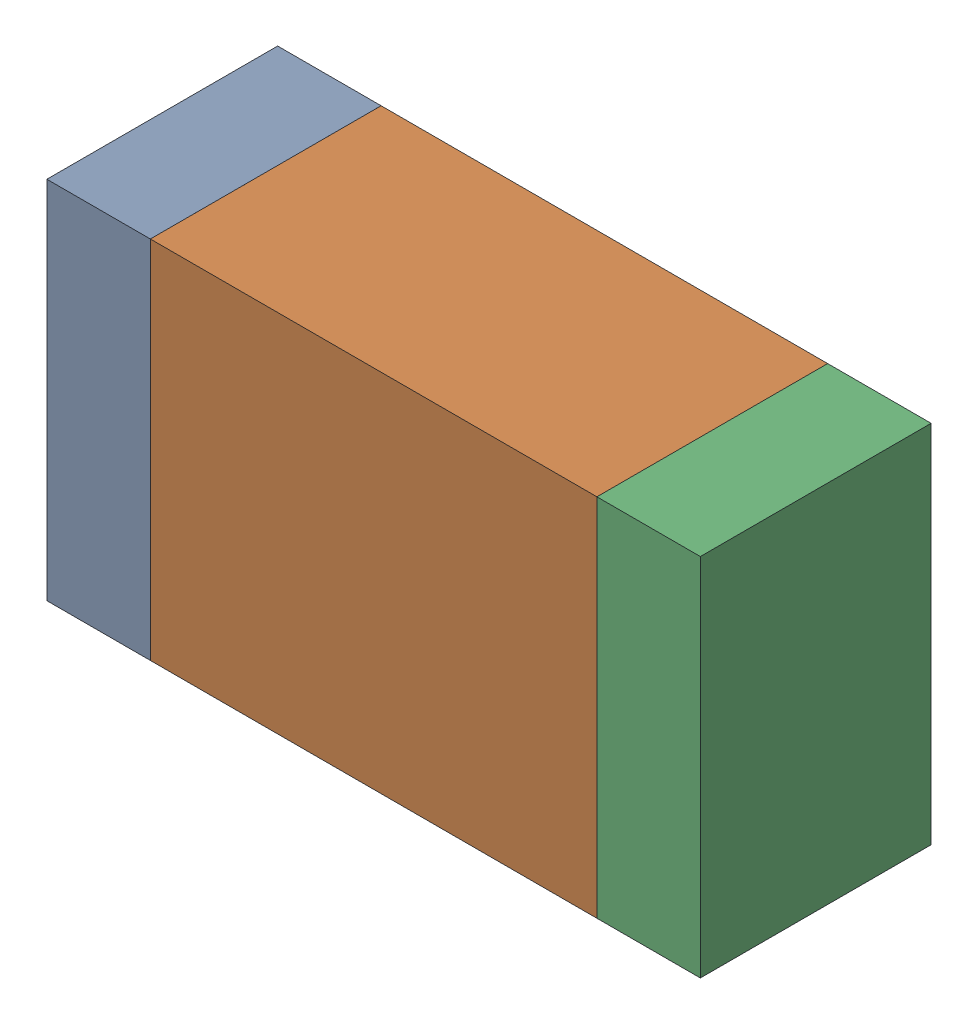
SolidWorks assembly F300_2PCB, configuration Default. Lengths in mm.
Overall size (1.7 0.95 0.6).
6 component instances, 2 part files, 0 mates.
Components (placement in the parent):
- 761615840-1: 761615840 [Default] at (159.7849 98.9999 0) size (0.27 0.95 0.6)
  - Extruded_37-1: Extruded_37 [Default] at origin size (0.27 0.95 0.6)
- 761615976-1: 761615976 [Default] at (160.4999 98.9999 0) size (1.16 0.95 0.6)
  - Extruded_38-1: Extruded_38 [Default] at origin size (1.16 0.95 0.6)
- 761615840-2: 761615840 [Default] at (161.2149 98.9999 0) size (0.27 0.95 0.6)
  - Extruded_37-1: Extruded_37 [Default] at origin size (0.27 0.95 0.6)
